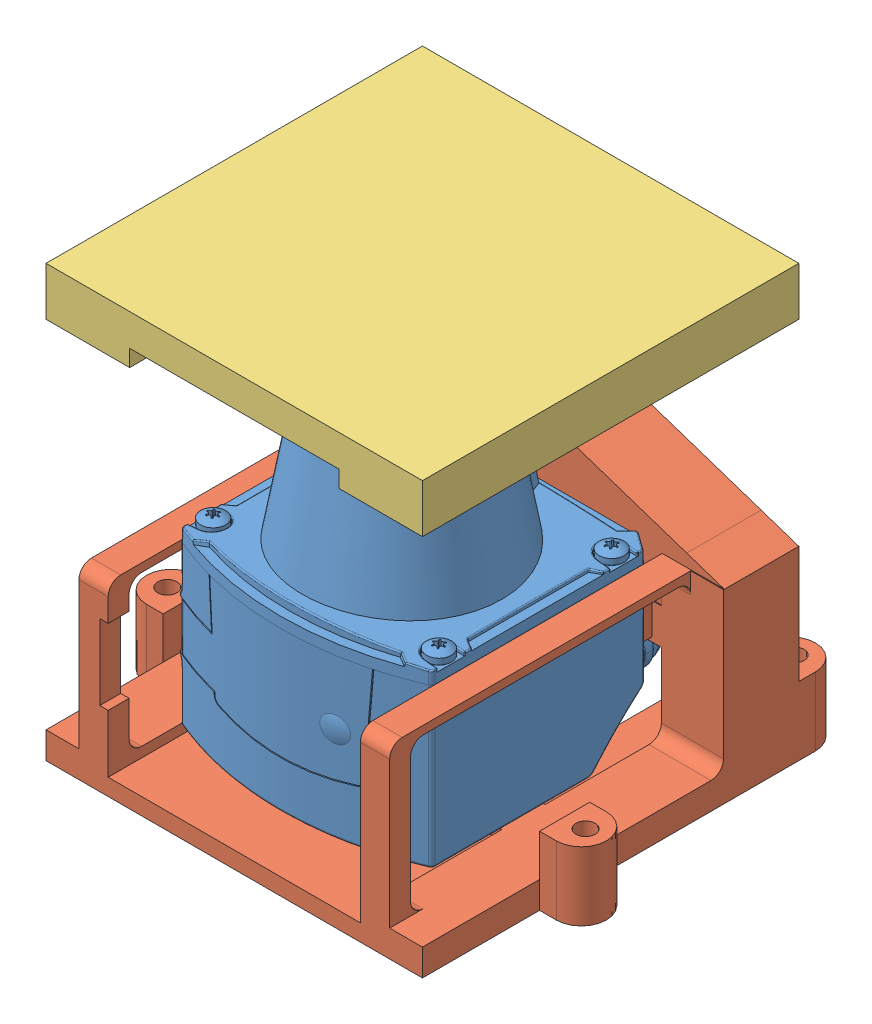
SolidWorks assembly Assemblage Support SICK TIM561 Robot 2, configuration Défaut. Lengths in mm.
Overall size (110 103 100).
3 component instances, 3 part files, 8 mates.
Components (placement in the parent):
- TIM561-Part-1: TIM561-Part [Default] at (-21.5594 -3.1762 118.1129) x (0 0 1) z (-1 0 0) size (76.29 86.12 61.14)
- Support Sick TIM562 Bas Robot 2-1: Support Sick TIM562 Bas Robot 2 [Défaut] at (-21.6123 -30.7341 113.1129) size (110 79 100)
- Support Sick TIM562 Haut Robot 2-1: Support Sick TIM562 Haut Robot 2 [Défaut] at (-21.6123 -30.7341 113.1129) size (90 39 90)
Mates (geometry in assembly coordinates):
- Coaxiale1: concentric anti-aligned: cylinder of Support Sick TIM561 MK1 B_M-1 through (19.8407 -7.8632 59.999) axis (0 0 1) radius 1.75; cylinder of TIM561-Part-1 through (5.2581 -11.3312 95.3031) axis (0 0 -1) radius 1.25
- Parallèle1: parallel anti-aligned: cylinder of Support Sick TIM561 MK1 B_M-1 through (-31.1593 -36.3042 121) axis (0 1 0) radius 1.75; cylinder of TIM561-Part-1 through (-45.7449 -33.2291 125.8031) axis (0 -1 0) radius 1.25
- Coïncidente1: coincident anti-aligned: plane of Support Sick TIM561 MK1 B_M-1 through (-5.7093 -36.3032 90.45) normal (0 0 1); plane of TIM561-Part-1 through (-45.3491 -11.3374 95.3031) normal (0 0 -1)
- Coaxiale2: concentric anti-aligned: circle of TIM561-Part-1; cylinder of Support Sick TIM562 Bas Robot 2-1 through (-47.0623 -30.7351 119.1129) axis (0 1 0) radius 1.75
- Coïncidente2: coincident anti-aligned: plane of TIM561-Part-1 through (-51.5594 -26.7341 93.5303) normal (0 -1 0); plane of Support Sick TIM562 Bas Robot 2-1 through (-21.6123 -26.7341 113.1129) normal (0 1 0)
- Coïncidente3: coincident aligned: plane of Support Sick TIM562 Bas Robot 2-1 through (-66.6123 -26.7341 68.1129) normal (0 0 -1); plane of Support Sick TIM562 Haut Robot 2-1 through (-66.6123 -26.7341 68.1129) normal (0 0 -1)
- Coïncidente4: coincident anti-aligned: plane of Support Sick TIM562 Bas Robot 2-1 through (-21.6123 48.2659 113.1129) normal (0 1 0); plane of Support Sick TIM562 Haut Robot 2-1 through (-21.6123 48.2659 113.1129) normal (0 -1 0)
- Coïncidente5: coincident aligned: plane of Support Sick TIM562 Bas Robot 2-1 through (-29.1123 60.6659 68.1129) normal (-1 0 0); plane of Support Sick TIM562 Haut Robot 2-1 through (-29.1123 60.6659 68.1129) normal (-1 0 0)
